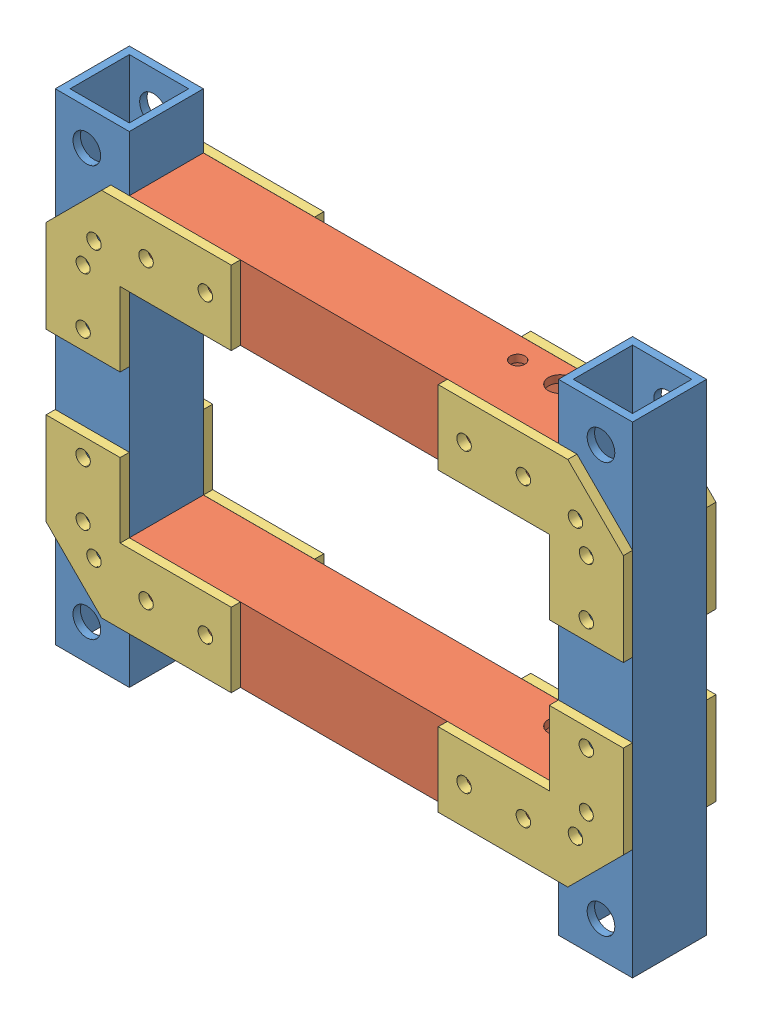
SolidWorks assembly Carriage Assembly, configuration Default. Lengths in mm.
Overall size (197.96 165.1 31.75).
12 component instances, 3 part files, 33 mates.
Components (placement in the parent):
- Carriage Frame Bar 6in-1: Carriage Frame Bar 6in [Default] at (66.8896 105.0895 106.2444) x (-1 0 0) z (0 0 -1) size (25.4 165.1 25.4)
- Carriage Fram Bar 4in-1: Carriage Fram Bar 4in [Bottom] at (41.4896 124.1395 80.8444) x (0 1 0) z (0 0 1) size (25.4 147.16 25.4)
- Carriage Frame Bar 6in-2: Carriage Frame Bar 6in [Default] at (-131.0662 105.0895 80.8444) size (25.4 165.1 25.4)
- Carriage Fram Bar 4in-2: Carriage Fram Bar 4in [Top] at (41.4896 225.7395 80.8444) x (0 1 0) z (0 0 1) size (25.4 147.16 25.4)
- CarriageGusset-1: CarriageGusset [Default] at (-131.0662 124.1395 77.644) size (63.5 50.8 3.17)
- CarriageGusset-2: CarriageGusset [Default] at (66.8896 251.1395 77.644) x (-1 0 0) z (0 0 1) size (63.5 50.8 3.17)
- CarriageGusset-3: CarriageGusset [Default] at (-131.0662 251.1395 80.819) x (1 0 0) z (0 0 -1) size (63.5 50.8 3.17)
- CarriageGusset-4: CarriageGusset [Default] at (66.8896 124.1395 80.819) x (-1 0 0) z (0 0 -1) size (63.5 50.8 3.17)
- CarriageGusset-5: CarriageGusset [Default] at (-131.0662 124.1395 106.219) size (63.5 50.8 3.17)
- CarriageGusset-6: CarriageGusset [Default] at (-131.0662 251.1395 109.394) x (1 0 0) z (0 0 -1) size (63.5 50.8 3.17)
- CarriageGusset-7: CarriageGusset [Default] at (66.8896 251.1395 106.219) x (-1 0 0) z (0 0 1) size (63.5 50.8 3.17)
- CarriageGusset-8: CarriageGusset [Default] at (66.8896 124.1395 109.394) x (-1 0 0) z (0 0 -1) size (63.5 50.8 3.17)
Mates (geometry in assembly coordinates):
- Coincident35: coincident anti-aligned: plane of Carriage Frame Bar 6in-2 through (-105.6662 270.1895 106.2444) normal (1 0 0); plane of Carriage Fram Bar 4in-2 through (-105.6662 225.7395 106.2444) normal (-1 0 0)
- Coincident36: coincident anti-aligned: line of Carriage Frame Bar 6in-2 through (-105.6662 105.0895 80.8444) axis (0 1 0); line of Carriage Fram Bar 4in-2 through (-105.6662 251.1395 80.8444) axis (0 -1 0)
- Distance6: distance = 19.05 mm: line of Carriage Fram Bar 4in-2 through (-105.6662 251.1395 106.2444) axis (0 0 -1); line of Carriage Frame Bar 6in-2 through (-105.6662 270.1895 106.2444) axis (0 0 -1)
- Coincident38: coincident anti-aligned: plane of Carriage Fram Bar 4in-1 through (-105.6662 124.1395 106.2444) normal (-1 0 0); plane of Carriage Frame Bar 6in-2 through (-105.6662 270.1895 106.2444) normal (1 0 0)
- Coincident39: coincident anti-aligned: line of Carriage Fram Bar 4in-1 through (-105.6662 149.5395 80.8444) axis (0 -1 0); line of Carriage Frame Bar 6in-2 through (-105.6662 105.0895 80.8444) axis (0 1 0)
- Distance7: distance = 19.05 mm: line of Carriage Fram Bar 4in-1 through (-105.6662 124.1395 106.2444) axis (0 0 -1); line of Carriage Frame Bar 6in-2 through (-105.6662 105.0895 106.2444) axis (0 0 -1)
- Coincident43: coincident anti-aligned: plane of Carriage Frame Bar 6in-1 through (41.4896 270.1895 80.8444) normal (-1 0 0); plane of Carriage Fram Bar 4in-2 through (41.4896 251.1395 106.2444) normal (1 0 0)
- Coincident44: coincident aligned: line of Carriage Frame Bar 6in-1 through (41.4896 105.0895 80.8444) axis (0 1 0); line of Carriage Fram Bar 4in-2 through (41.4896 225.7395 80.8444) axis (0 1 0)
- Distance8: distance = 19.05 mm: line of Carriage Frame Bar 6in-1 through (41.4896 270.1895 80.8444) axis (0 0 1); line of Carriage Fram Bar 4in-2 through (41.4896 251.1395 106.2444) axis (0 0 -1)
- Coincident50: coincident aligned: plane of Carriage Frame Bar 6in-2 through (-105.6662 270.1895 106.2444) normal (1 0 0); plane of CarriageGusset-1 through (-105.6662 149.5395 80.819) normal (1 0 0)
- Coincident51: coincident aligned: plane of Carriage Fram Bar 4in-1 through (-105.6662 149.5395 106.2444) normal (0 1 0); plane of CarriageGusset-1 through (-67.5662 149.5395 80.819) normal (0 1 0)
- Coincident53: coincident aligned: plane of Carriage Frame Bar 6in-1 through (41.4896 270.1895 80.8444) normal (-1 0 0); plane of CarriageGusset-4 through (41.4896 149.5395 77.644) normal (-1 0 0)
- Coincident54: coincident aligned: plane of Carriage Fram Bar 4in-1 through (-105.6662 149.5395 106.2444) normal (0 1 0); plane of CarriageGusset-4 through (3.3896 149.5395 77.644) normal (0 1 0)
- Coincident56: coincident aligned: plane of Carriage Fram Bar 4in-2 through (41.4896 225.7395 106.2444) normal (0 -1 0); plane of CarriageGusset-3 through (-67.5662 225.7395 77.644) normal (0 -1 0)
- Coincident57: coincident aligned: plane of CarriageGusset-3 through (-105.6662 225.7395 77.644) normal (1 0 0); plane of Carriage Frame Bar 6in-2 through (-105.6662 270.1895 106.2444) normal (1 0 0)
- Distance9: distance = 0.0254 mm anti-aligned: plane of CarriageGusset-2 through (66.8896 251.1395 80.819) normal (0 0 1); plane of Carriage Fram Bar 4in-2 through (41.4896 225.7395 80.8444) normal (0 0 -1)
- Coincident60: coincident aligned: plane of Carriage Fram Bar 4in-2 through (41.4896 225.7395 106.2444) normal (0 -1 0); plane of CarriageGusset-2 through (3.3896 225.7395 80.819) normal (0 -1 0)
- Coincident61: coincident aligned: plane of Carriage Frame Bar 6in-1 through (41.4896 270.1895 80.8444) normal (-1 0 0); plane of CarriageGusset-2 through (41.4896 225.7395 80.819) normal (-1 0 0)
- Coincident62: coincident aligned: plane of CarriageGusset-2 through (66.8896 251.1395 77.644) normal (0 0 -1); plane of CarriageGusset-3 through (-131.0662 251.1395 77.644) normal (0 0 -1)
- Coincident63: coincident aligned: plane of CarriageGusset-1 through (-131.0662 124.1395 77.644) normal (0 0 -1); plane of CarriageGusset-3 through (-131.0662 251.1395 77.644) normal (0 0 -1)
- Coincident64: coincident aligned: plane of CarriageGusset-1 through (-131.0662 124.1395 77.644) normal (0 0 -1); plane of CarriageGusset-4 through (66.8896 124.1395 77.644) normal (0 0 -1)
- Distance10: distance = 0.0254 mm anti-aligned: plane of CarriageGusset-6 through (-131.0662 251.1395 106.219) normal (0 0 -1); plane of Carriage Frame Bar 6in-2 through (-131.0662 105.0895 106.2444) normal (0 0 1)
- Coincident66: coincident aligned: plane of Carriage Fram Bar 4in-2 through (-105.6662 251.1395 106.2444) normal (0 1 0); plane of CarriageGusset-6 through (-131.0662 251.1395 106.219) normal (0 1 0)
- Coincident67: coincident aligned: plane of Carriage Frame Bar 6in-2 through (-131.0662 105.0895 106.2444) normal (-1 0 0); plane of CarriageGusset-6 through (-131.0662 251.1395 106.219) normal (-1 0 0)
- Coincident68: coincident aligned: plane of Carriage Frame Bar 6in-2 through (-131.0662 105.0895 106.2444) normal (-1 0 0); plane of CarriageGusset-5 through (-131.0662 124.1395 109.394) normal (-1 0 0)
- Coincident69: coincident aligned: plane of CarriageGusset-5 through (-131.0662 124.1395 109.394) normal (0 0 1); plane of CarriageGusset-6 through (-131.0662 251.1395 109.394) normal (0 0 1)
- Coincident70: coincident aligned: plane of Carriage Fram Bar 4in-1 through (41.4896 124.1395 106.2444) normal (0 -1 0); plane of CarriageGusset-5 through (-131.0662 124.1395 109.394) normal (0 -1 0)
- Coincident71: coincident aligned: plane of Carriage Fram Bar 4in-1 through (41.4896 124.1395 106.2444) normal (0 -1 0); plane of CarriageGusset-8 through (66.8896 124.1395 106.219) normal (0 -1 0)
- Coincident72: coincident aligned: plane of Carriage Frame Bar 6in-1 through (66.8896 105.0895 80.8444) normal (1 0 0); plane of CarriageGusset-8 through (66.8896 124.1395 106.219) normal (1 0 0)
- Coincident73: coincident aligned: plane of CarriageGusset-6 through (-131.0662 251.1395 109.394) normal (0 0 1); plane of CarriageGusset-8 through (66.8896 124.1395 109.394) normal (0 0 1)
- Coincident74: coincident aligned: plane of CarriageGusset-6 through (-131.0662 251.1395 109.394) normal (0 0 1); plane of CarriageGusset-7 through (66.8896 251.1395 109.394) normal (0 0 1)
- Coincident75: coincident aligned: plane of Carriage Frame Bar 6in-1 through (66.8896 105.0895 80.8444) normal (1 0 0); plane of CarriageGusset-7 through (66.8896 251.1395 109.394) normal (1 0 0)
- Coincident76: coincident aligned: plane of Carriage Fram Bar 4in-2 through (-105.6662 251.1395 106.2444) normal (0 1 0); plane of CarriageGusset-7 through (66.8896 251.1395 109.394) normal (0 1 0)
